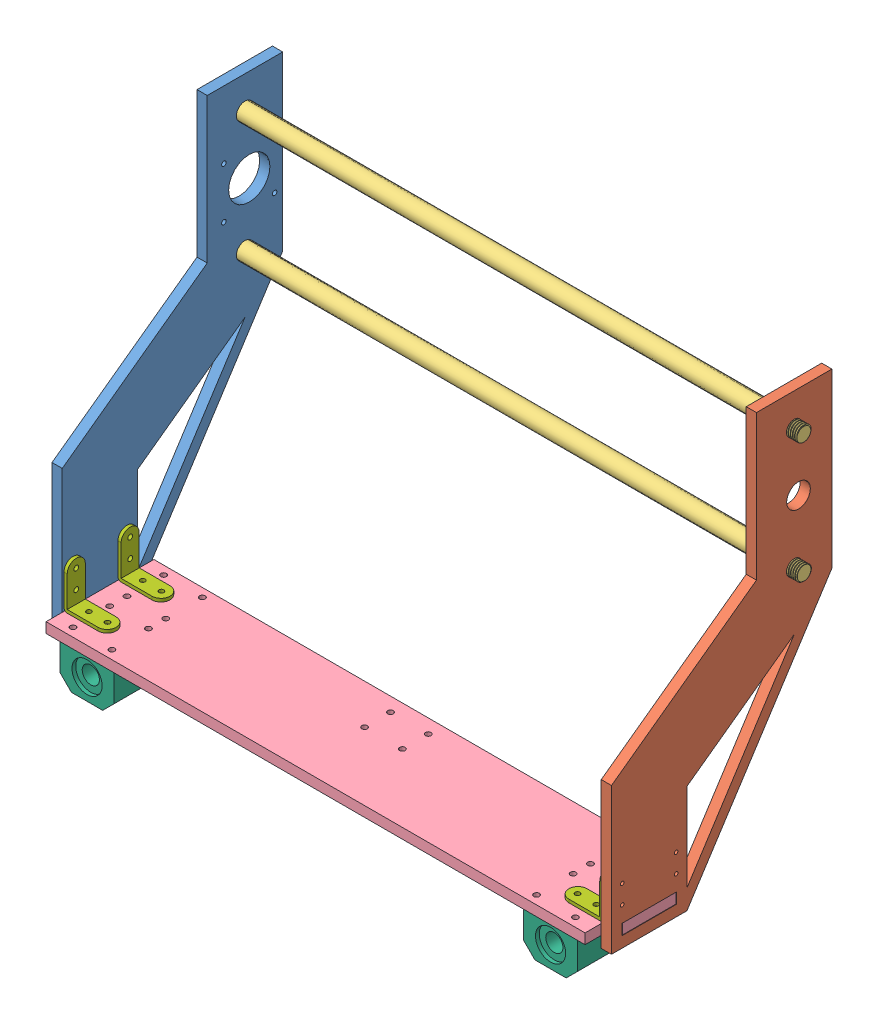
SolidWorks assembly X frame, configuration Default. Lengths in mm.
Overall size (539.39 396 219.5).
14 component instances, 7 part files, 20 mates.
Components (placement in the parent):
- X left panel-2: X left panel [Default] at (38.9126 159.7042 -3.8915) x (-1 0 0) z (0 0 -1) size (9.5 368 204.5)
- X right panel-2: X right panel [Default] at (548.4126 159.7042 -3.8915) x (-1 0 0) z (0 0 -1) size (9.5 368 204.5)
- X rod-1: X rod [Default] at (488.8896 497.7042 -103.3915) x (0 0.241484 -0.970405) z (1 0 0) size (16 16 539.39)
- X rod-2: X rod [Default] at (488.8896 385.7042 -103.3915) x (0 -0.574929 -0.818203) z (1 0 0) size (16 16 539.39)
- Y sliding panel-1: Y sliding panel [Default] at (288.9126 179.7042 31.1085) x (1 0 0) z (0 -1 0) size (519 100 9.5)
- screw block-1: screw block [Default] at (288.9126 155.2042 24.1085) x (-1 0 0) z (0 0 -1) size (50 30 47.5)
- sliding block-1: sliding block [Default] at (503.9126 131.7042 6.1085) x (1 0 0) z (0 1 0) size (50 44 38.5)
- sliding block-2: sliding block [Default] at (503.9126 131.7042 56.1085) x (1 0 0) z (0 1 0) size (50 44 38.5)
- sliding block-3: sliding block [Default] at (73.9126 131.7042 6.1085) x (1 0 0) z (0 1 0) size (50 44 38.5)
- sliding block-4: sliding block [Default] at (73.9126 131.7042 56.1085) x (1 0 0) z (0 1 0) size (50 44 38.5)
- corner connector #40-1: corner connector #40 [Default] at (38.9126 195.5042 6.1085) x (0 0 -1) z (1 0 0) size (16.8 40 40)
- corner connector #40-2: corner connector #40 [Default] at (38.9126 195.5042 56.1085) x (0 0 -1) z (1 0 0) size (16.8 40 40)
- corner connector #40-3: corner connector #40 [Default] at (538.9126 195.5042 6.1085) x (0 0 1) z (-1 0 0) size (16.8 40 40)
- corner connector #40-4: corner connector #40 [Default] at (538.9126 195.5042 56.1085) x (0 0 1) z (-1 0 0) size (16.8 40 40)
Mates (geometry in assembly coordinates):
- ProfileCenter14: profile center = 0 mm anti-aligned: circle of sliding block-4; circle of Y sliding panel-1
- Concentric1: concentric aligned: cylinder of Y sliding panel-1 through (91.9126 170.2042 39.1085) axis (0 1 0) radius 2.6; cylinder of sliding block-4 through (91.9126 170.2042 39.1085) axis (0 1 0) radius 2.1
- ProfileCenter15: profile center = 0 mm anti-aligned: circle of sliding block-3; circle of Y sliding panel-1
- Concentric2: concentric aligned: cylinder of Y sliding panel-1 through (91.9126 170.2042 -10.8915) axis (0 1 0) radius 2.6; cylinder of sliding block-3 through (91.9126 170.2042 -10.8915) axis (0 1 0) radius 2.1
- ProfileCenter16: profile center = 0 mm anti-aligned: circle of Y sliding panel-1; circle of sliding block-2
- ProfileCenter17: profile center = 0 mm anti-aligned: circle of sliding block-1; circle of Y sliding panel-1
- Concentric3: concentric aligned: cylinder of Y sliding panel-1 through (485.9126 170.2042 -10.8915) axis (0 1 0) radius 2.6; cylinder of sliding block-1 through (485.9126 170.2042 -10.8915) axis (0 1 0) radius 2.1
- Concentric4: concentric aligned: cylinder of Y sliding panel-1 through (485.9126 170.2042 39.1085) axis (0 1 0) radius 2.6; cylinder of sliding block-2 through (485.9126 170.2042 39.1085) axis (0 1 0) radius 2.1
- ProfileCenter18: profile center = 0 mm anti-aligned: circle of screw block-1; circle of Y sliding panel-1
- Concentric5: concentric aligned: cylinder of Y sliding panel-1 through (271.4126 170.2042 -5.8915) axis (0 1 0) radius 2.6; cylinder of screw block-1 through (271.4126 170.2042 -5.8915) axis (0 1 0) radius 2.1
- ProfileCenter19: profile center = 0 mm aligned: circle of corner connector #40-1; circle of Y sliding panel-1
- ProfileCenter20: profile center = 0 mm anti-aligned: circle of X left panel-2; circle of corner connector #40-1
- Concentric20: concentric aligned: cylinder of X left panel-2 through (29.4126 211.7042 56.1085) axis (-1 0 0) radius 1.65; cylinder of corner connector #40-2 through (41.9126 211.7042 56.1085) axis (-1 0 0) radius 2.25
- ProfileCenter21: profile center = 0 mm aligned: circle of corner connector #40-2; circle of Y sliding panel-1
- ProfileCenter22: profile center = 0 mm aligned: circle of Y sliding panel-1; circle of corner connector #40-3
- ProfileCenter23: profile center = 0 mm aligned: circle of X right panel-2; circle of corner connector #40-3
- ProfileCenter24: profile center = 0 mm aligned: circle of Y sliding panel-1; circle of corner connector #40-4
- Concentric21: concentric anti-aligned: cylinder of X right panel-2 through (538.9126 211.7042 56.1085) axis (-1 0 0) radius 1.65; cylinder of corner connector #40-4 through (535.9126 211.7042 56.1085) axis (1 0 0) radius 2.25
- ProfileCenter25: profile center = 0 mm anti-aligned: circle of X rod-1; circle of X left panel-2
- ProfileCenter26: profile center = 0 mm anti-aligned: circle of X rod-2; circle of X left panel-2
